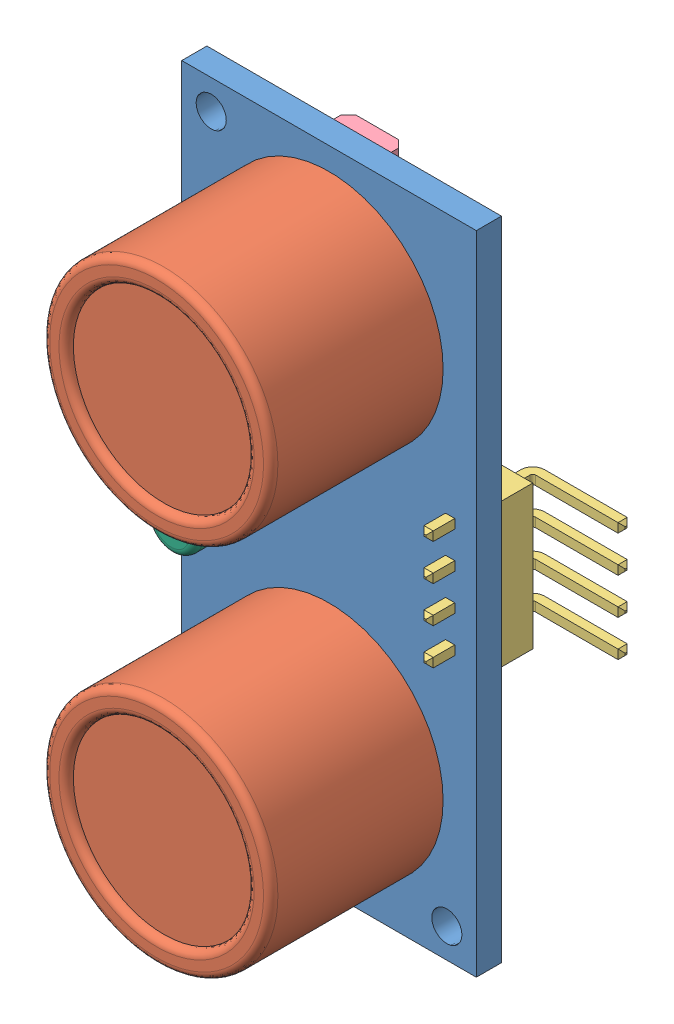
SolidWorks assembly HC-SR04 Ping Sensor, configuration Default. Lengths in mm.
Overall size (25.18 45 18.07).
14 component instances, 6 part files, 46 mates.
Components (placement in the parent):
- PCB-1: PCB [Default] at origin size (20.5 45 1.75)
- Transducer-1: Transducer [Default] at (0 -13 13.25) x (1 0 0) z (0 -1 0) size (15.88 12 15.88)
- Transducer-2: Transducer [Default] at (0 13 13.25) x (1 0 0) z (0 -1 0) size (15.88 12 15.88)
- 3 Pin Header 90 Degree-1: 3 Pin Header 90 Degree [Default] at (8.4275 0 -1.25) x (-1 0 0) z (0 -1 0) size (8 7.82 10)
- 14 Pin SMT-1: 14 Pin SMT [Default] at (-0.35 -18.5 -0.85) x (0 -1 0) z (1 0 0) size (6 1.6 8.8)
- 14 Pin SMT-2: 14 Pin SMT [Default] at (0 -0.3826 -0.85) x (1 0 0) z (0 1 0) size (6 1.6 8.8)
- 14 Pin SMT-3: 14 Pin SMT [Default] at (0 17.5274 -0.85) x (1 0 0) z (0 1 0) size (6 1.6 8.8)
- Cap1 SMT-1: Cap1 SMT [Default] at (-1.755 7.4774 -0.9689) x (0 1 0) z (-1 0 0) size (4.5 1.84 1.75)
- Cap1 SMT-2: Cap1 SMT [Default] at (6.835 7.4774 -0.9689) x (0 1 0) z (-1 0 0) size (4.5 1.84 1.75)
- Cap1 SMT-3: Cap1 SMT [Default] at (-6.835 7.4774 -0.9689) x (0 1 0) z (-1 0 0) size (4.5 1.84 1.75)
- Cap1 SMT-4: Cap1 SMT [Default] at (4.295 7.4774 -0.9689) x (0 1 0) z (-1 0 0) size (4.5 1.84 1.75)
- Cap1 SMT-5: Cap1 SMT [Default] at (1.755 7.4774 -0.9689) x (0 1 0) z (-1 0 0) size (4.5 1.84 1.75)
- Cap1 SMT-6: Cap1 SMT [Default] at (-4.295 7.4774 -0.9689) x (0 1 0) z (-1 0 0) size (4.5 1.84 1.75)
- HC-SR04 Crystal-1: HC-SR04 Crystal [Default] at (-8.3 0 1.75) x (0 -1 0) z (0 0 1) size (10 3.5 2.7)
Mates (geometry in assembly coordinates):
- Coincident1: coincident: plane of PCB-1 through (-10.25 -22.5 1.75) normal (0 0 1); plane of Transducer-2 through (0 12.34 1.75) normal (0 0 -1)
- Coincident2: coincident: plane of PCB-1 through (-10.25 -22.5 1.75) normal (0 0 1); plane of Transducer-1 through (0 -13.16 1.75) normal (0 0 -1)
- Coincident3: coincident: plane of PCB-1 through (0 0 0) normal (1 0 0); plane of Transducer-1 through (0 -13.16 13.25) normal (1 0 0)
- Coincident4: coincident: plane of PCB-1 through (0 0 0) normal (1 0 0); plane of Transducer-2 through (0 12.34 13.25) normal (1 0 0)
- Distance2: distance = 9.5 mm: plane of PCB-1 through (-10.25 -22.5 1.75) normal (0 -1 0); point of Transducer-1
- Distance3: distance = 9.5 mm: plane of PCB-1 through (-10.25 22.5 1.75) normal (0 1 0); point of Transducer-2
- Coincident8: coincident: plane of PCB-1 through (0 0 0) normal (0 1 0); plane of 3 Pin Header 90 Degree-1 through (8.4275 0 -1.25) normal (0 -1 0)
- Coincident9: coincident: plane of PCB-1 through (-10.25 -22.5 0) normal (0 0 -1); plane of 14 Pin SMT-1 through (-0.6 -21.5 0) normal (0 0 1)
- Coincident10: coincident: plane of PCB-1 through (-10.25 -22.5 0) normal (0 0 -1); plane of 14 Pin SMT-2 through (3 -0.6326 0) normal (0 0 1)
- Coincident11: coincident: plane of PCB-1 through (-10.25 -22.5 0) normal (0 0 -1); plane of 14 Pin SMT-3 through (3 18.5274 0) normal (0 0 1)
- Coincident13: coincident: plane of PCB-1 through (0 0 0) normal (1 0 0); plane of 14 Pin SMT-2 through (0 -0.3826 -0.85) normal (1 0 0)
- Coincident14: coincident: plane of PCB-1 through (0 0 0) normal (1 0 0); plane of 14 Pin SMT-3 through (0 17.5274 -0.85) normal (1 0 0)
- Distance6: distance = 9.11 mm: plane of 14 Pin SMT-2 through (-2 4.0174 -1.6) normal (0 1 0); plane of 14 Pin SMT-3 through (-2 13.1274 -1.6) normal (0 -1 0)
- Coincident15: coincident: plane of PCB-1 through (-10.25 -22.5 0) normal (0 0 -1); plane of Cap1 SMT-1 through (-2.005 9.7274 0) normal (0 0 1)
- Coincident16: coincident: plane of PCB-1 through (-10.25 -22.5 0) normal (0 0 -1); plane of Cap1 SMT-2 through (6.585 9.7274 0) normal (0 0 1)
- Coincident17: coincident: plane of PCB-1 through (-10.25 -22.5 0) normal (0 0 -1); plane of Cap1 SMT-3 through (-7.085 9.7274 0) normal (0 0 1)
- Coincident18: coincident: plane of PCB-1 through (-10.25 -22.5 0) normal (0 0 -1); plane of Cap1 SMT-4 through (4.045 9.7274 0) normal (0 0 1)
- Coincident19: coincident: plane of PCB-1 through (-10.25 -22.5 0) normal (0 0 -1); plane of Cap1 SMT-5 through (1.505 9.7274 0) normal (0 0 1)
- Coincident20: coincident: plane of PCB-1 through (-10.25 -22.5 0) normal (0 0 -1); plane of Cap1 SMT-6 through (-4.545 9.7274 0) normal (0 0 1)
- Parallel1: parallel: plane of Cap1 SMT-4 through (3.42 5.7274 -1.8439) normal (0 -1 0); plane of Cap1 SMT-5 through (0.88 5.7274 -1.8439) normal (0 -1 0)
- Parallel2: parallel: plane of Cap1 SMT-2 through (5.96 5.7274 -1.8439) normal (0 -1 0); plane of Cap1 SMT-4 through (3.42 5.7274 -1.8439) normal (0 -1 0)
- Parallel3: parallel: plane of PCB-1 through (-10.25 -22.5 1.75) normal (0 -1 0); plane of Cap1 SMT-2 through (5.96 5.7274 -1.8439) normal (0 -1 0)
- Distance7: distance = 0.79 mm: plane of Cap1 SMT-2 through (5.96 5.7274 -1.8439) normal (-1 0 0); plane of Cap1 SMT-4 through (5.17 5.7274 -1.8439) normal (1 0 0)
- Distance8: distance = 0.79 mm: plane of Cap1 SMT-4 through (3.42 5.7274 -1.8439) normal (-1 0 0); plane of Cap1 SMT-5 through (2.63 5.7274 -1.8439) normal (1 0 0)
- Distance9: distance = 2.54 mm: plane of PCB-1 through (10.25 22.5 1.75) normal (1 0 0); plane of Cap1 SMT-2 through (7.71 5.7274 -1.8439) normal (1 0 0)
- Coincident21: coincident: plane of Cap1 SMT-4 through (3.42 9.2274 -0.0939) normal (0 1 0); plane of Cap1 SMT-5 through (0.88 9.2274 -0.0939) normal (0 1 0)
- Coincident22: coincident: plane of Cap1 SMT-2 through (5.96 9.2274 -0.0939) normal (0 1 0); plane of Cap1 SMT-4 through (3.42 9.2274 -0.0939) normal (0 1 0)
- Parallel4: parallel: plane of Cap1 SMT-3 through (-7.71 5.7274 -1.8439) normal (0 -1 0); plane of Cap1 SMT-6 through (-5.17 5.7274 -1.8439) normal (0 -1 0)
- Parallel5: parallel: plane of Cap1 SMT-1 through (-2.63 5.7274 -1.8439) normal (0 -1 0); plane of Cap1 SMT-6 through (-5.17 5.7274 -1.8439) normal (0 -1 0)
- Distance11: distance = 0.79 mm: plane of Cap1 SMT-1 through (-2.63 5.7274 -1.8439) normal (-1 0 0); plane of Cap1 SMT-6 through (-3.42 5.7274 -1.8439) normal (1 0 0)
- Distance12: distance = 0.79 mm: plane of Cap1 SMT-3 through (-5.96 5.7274 -1.8439) normal (1 0 0); plane of Cap1 SMT-6 through (-5.17 5.7274 -1.8439) normal (-1 0 0)
- Coincident23: coincident: plane of Cap1 SMT-3 through (-7.71 9.2274 -0.0939) normal (0 1 0); plane of Cap1 SMT-6 through (-5.17 9.2274 -0.0939) normal (0 1 0)
- Coincident24: coincident: plane of Cap1 SMT-1 through (-2.63 9.2274 -0.0939) normal (0 1 0); plane of Cap1 SMT-6 through (-5.17 9.2274 -0.0939) normal (0 1 0)
- Parallel6: parallel: plane of PCB-1 through (-10.25 -22.5 1.75) normal (0 -1 0); plane of Cap1 SMT-3 through (-7.71 5.7274 -1.8439) normal (0 -1 0)
- Distance13: distance = 2.54 mm: plane of PCB-1 through (-10.25 22.5 1.75) normal (-1 0 0); plane of Cap1 SMT-3 through (-7.71 5.7274 -1.8439) normal (-1 0 0)
- Coincident25: coincident: plane of Cap1 SMT-1 through (-2.63 9.2274 -0.0939) normal (0 1 0); plane of Cap1 SMT-5 through (0.88 9.2274 -0.0939) normal (0 1 0)
- Distance15: distance = 1.71 mm: plane of 14 Pin SMT-2 through (-2 4.0174 -1.6) normal (0 1 0); plane of Cap1 SMT-5 through (0.88 5.7274 -1.8439) normal (0 -1 0)
- Coincident26: coincident: plane of PCB-1 through (-10.25 -22.5 0) normal (0 0 -1); plane of 3 Pin Header 90 Degree-1 through (9.9275 -5 0) normal (0 0 1)
- Distance16: distance = 1.5 mm: plane of 3 Pin Header 90 Degree-1 through (8.75 4.4 -2.5) normal (1 0 0); plane of PCB-1 through (10.25 22.5 1.75) normal (1 0 0)
- Parallel7: parallel: plane of PCB-1 through (-10.25 22.5 1.75) normal (-1 0 0); plane of 14 Pin SMT-1 through (4.05 -16.5 -1.6) normal (1 0 0)
- Distance17: distance = 5.5 mm: plane of 14 Pin SMT-1 through (-4.75 -16.5 -1.6) normal (-1 0 0); plane of PCB-1 through (-10.25 22.5 1.75) normal (-1 0 0)
- Distance18: distance = 2 mm: plane of 14 Pin SMT-1 through (4.05 -20.5 -0.1) normal (0 -1 0); plane of PCB-1 through (-10.25 -22.5 1.75) normal (0 -1 0)
- Distance19: distance = 0.5726 mm: plane of 14 Pin SMT-3 through (-2 21.9274 -1.6) normal (0 1 0); plane of PCB-1 through (-10.25 22.5 1.75) normal (0 1 0)
- Distance20: distance = 0.2 mm: plane of PCB-1 through (-10.25 22.5 1.75) normal (-1 0 0); plane of HC-SR04 Crystal-1 through (-10.05 3.25 4.45) normal (-1 0 0)
- Coincident36: coincident: plane of PCB-1 through (-10.25 -22.5 1.75) normal (0 0 1); plane of HC-SR04 Crystal-1 through (-8.3 3.25 1.75) normal (0 0 -1)
- Coincident37: coincident: plane of HC-SR04 Crystal-1 through (-8.3 0 1.75) normal (0 -1 0); plane of assembly through (0 0 0) normal (0 1 0)
